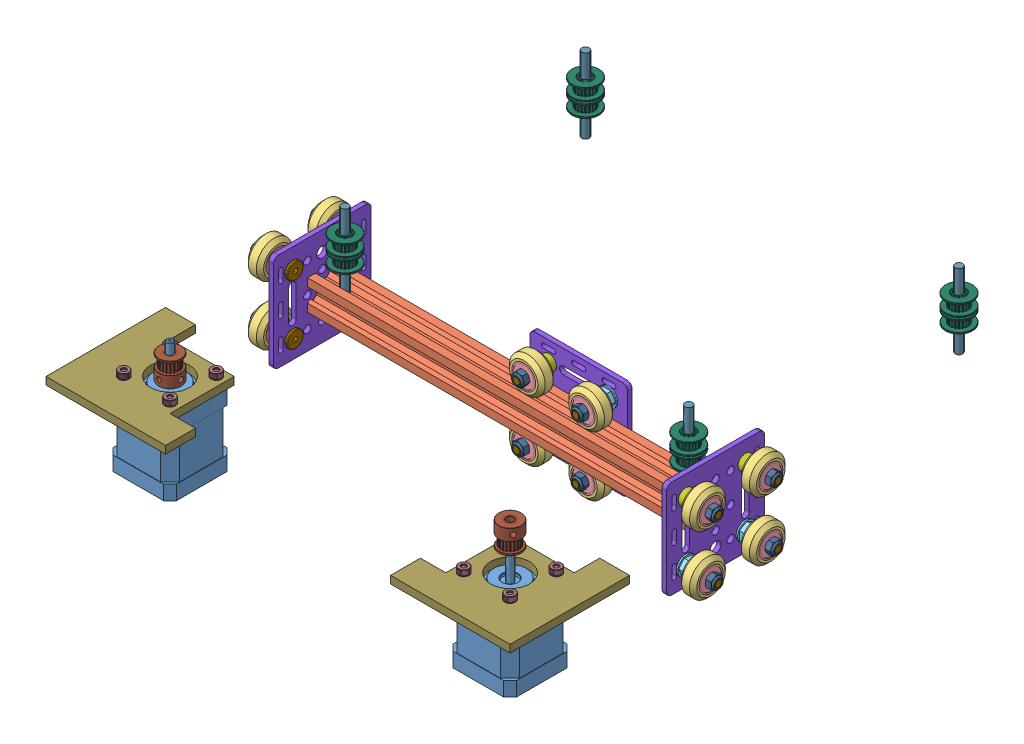
SolidWorks assembly XY_Axis_motion, configuration Default. Lengths in mm.
Overall size (310.6 92.07 339.8).
129 component instances, 15 part files, 36 mates.
Components (placement in the parent):
- DC_Steppers-1: DC_Steppers [6627T91] at (113.8 319.013 128.8) x (1 0 0) z (0 1 0) size (42.4 43.16 74.07)
- V-slot-aluminum-1: V-slot-aluminum [Gantry] at (130 320 10.5363) x (0 0 1) z (-1 0 0) size (20 20 260)
- DC_Steppers-2: DC_Steppers [6627T91] at (-113.8 319.013 128.8) x (1 0 0) z (0 1 0) size (42.4 43.16 74.07)
- 20mm Gantry Set.stp-1: 20mm Gantry Set.stp [Default] at (-145 320 10.5363) x (0 1 0) z (-1 0 0) size (71.69 71.99 27)
  - V-Wheel Solid Wheel.stp-1: V-Wheel Solid Wheel.stp [Default] at (31.4376 30.3864 0.786) x (0.859314 0.511448 0) z (0.511448 -0.859314 0) size (23.9 20 23.9)
    - Solid V-Wheel.stp-1: Solid V-Wheel.stp [Default] at (-15.2695 -5.901 2.9988) size (23.9 10.23 23.9)
    - Ball Bearing 625 2RS 5x16x5.stp-1: Ball Bearing 625 2RS 5x16x5.stp [Default] at (-15.2695 -5.671 2.9988) x (1 0 0) z (0 1 0) size (16 16 5)
    - Ball Bearing 625 2RS 5x16x5.stp-2: Ball Bearing 625 2RS 5x16x5.stp [Default] at (-15.2695 -0.671 2.9988) x (0.579467 0 0.814996) z (0 1 0) size (16 16 5)
    - Eccentric Spacer.stp-1: Eccentric Spacer.stp [Default] at (-15.2695 -6.671 2.9988) x (1 0 0) z (0 -1 0) size (12.5 12.5 9)
    - 1mm 5mm shim.stp-1: 1mm 5mm shim.stp [Default] at (-15.2695 -5.671 2.9988) x (1 0 0) z (0 -1 0) size (10 10 1)
  - V-Wheel Solid Wheel.stp-2: V-Wheel Solid Wheel.stp [Default] at (28.1904 -33.1373 0.786) x (0.363236 -0.931697 0) z (-0.931697 -0.363236 0) size (23.9 20 23.9)
    - Solid V-Wheel.stp-1: Solid V-Wheel.stp [Default] at (-15.2695 -5.901 2.9988) size (23.9 10.23 23.9)
    - Ball Bearing 625 2RS 5x16x5.stp-1: Ball Bearing 625 2RS 5x16x5.stp [Default] at (-15.2695 -5.671 2.9988) x (1 0 0) z (0 1 0) size (16 16 5)
    - Ball Bearing 625 2RS 5x16x5.stp-2: Ball Bearing 625 2RS 5x16x5.stp [Default] at (-15.2695 -0.671 2.9988) x (0.579467 0 0.814996) z (0 1 0) size (16 16 5)
    - Eccentric Spacer.stp-1: Eccentric Spacer.stp [Default] at (-15.2695 -6.671 2.9988) x (1 0 0) z (0 -1 0) size (12.5 12.5 9)
    - 1mm 5mm shim.stp-1: 1mm 5mm shim.stp [Default] at (-15.2695 -5.671 2.9988) x (1 0 0) z (0 -1 0) size (10 10 1)
  - V-Wheel Solid Wheel - spacer.stp-1: V-Wheel Solid Wheel - spacer.stp [Default] at (-4.4084 21.9251 0.786) x (0.997558 -0.069836 0) z (-0.069836 -0.997558 0) size (23.9 17 23.9)
    - Solid V-Wheel.stp-1: Solid V-Wheel.stp [Default] at (-15.2695 -5.901 2.9988) size (23.9 10.23 23.9)
    - Ball Bearing 625 2RS 5x16x5.stp-1: Ball Bearing 625 2RS 5x16x5.stp [Default] at (-15.2695 -5.671 2.9988) x (1 0 0) z (0 1 0) size (16 16 5)
    - Ball Bearing 625 2RS 5x16x5.stp-2: Ball Bearing 625 2RS 5x16x5.stp [Default] at (-15.2695 -0.671 2.9988) x (0.579467 0 0.814996) z (0 1 0) size (16 16 5)
    - 1mm 5mm shim.stp-1: 1mm 5mm shim.stp [Default] at (-15.2695 -5.671 2.9988) x (1 0 0) z (0 -1 0) size (10 10 1)
    - 6mm Spacer.stp-1: 6mm Spacer.stp [Default] at (-15.2695 -6.671 2.9988) x (1 0 0) z (0 -1 0) size (10 10 6)
  - V-Wheel Solid Wheel - spacer.stp-2: V-Wheel Solid Wheel - spacer.stp [Default] at (-6.8841 -11.3956 0.786) x (0.92416 0.382005 0) z (0.382005 -0.92416 0) size (23.9 17 23.9)
    - Solid V-Wheel.stp-1: Solid V-Wheel.stp [Default] at (-15.2695 -5.901 2.9988) size (23.9 10.23 23.9)
    - Ball Bearing 625 2RS 5x16x5.stp-1: Ball Bearing 625 2RS 5x16x5.stp [Default] at (-15.2695 -5.671 2.9988) x (1 0 0) z (0 1 0) size (16 16 5)
    - Ball Bearing 625 2RS 5x16x5.stp-2: Ball Bearing 625 2RS 5x16x5.stp [Default] at (-15.2695 -0.671 2.9988) x (0.579467 0 0.814996) z (0 1 0) size (16 16 5)
    - 1mm 5mm shim.stp-1: 1mm 5mm shim.stp [Default] at (-15.2695 -5.671 2.9988) x (1 0 0) z (0 -1 0) size (10 10 1)
    - 6mm Spacer.stp-1: 6mm Spacer.stp [Default] at (-15.2695 -6.671 2.9988) x (1 0 0) z (0 -1 0) size (10 10 6)
  - 20mm gantry plate.stp-1: 20mm gantry plate.stp [Default] at (0 0 -14.885) size (65.5 65.5 3)
  - M5x25 low profile screw.stp-1: M5x25 low profile screw.stp [Default] at (19.85 -20 -16.885) x (0.999998 -0.001827 0) z (0 0 1) size (11 11 27)
  - M5x25 low profile screw.stp-2: M5x25 low profile screw.stp [Default] at (19.85 20 -16.885) x (1 0.000182 0) z (0 0 1) size (11 11 27)
  - M5x25 low profile screw.stp-3: M5x25 low profile screw.stp [Default] at (-19.85 -20 -16.885) x (0.999594 -0.02849 0) z (0 0 1) size (11 11 27)
  - M5 Nylock.stp-1: M5 Nylock.stp [Default] at (19.85 -20 5.115) x (-0.864363 0.502868 0) z (0 0 1) size (9.24 9.25 5)
  - M5 Nylock.stp-2: M5 Nylock.stp [Default] at (19.85 20 5.115) x (0.463993 -0.885839 0) z (0 0 1) size (9.24 9.25 5)
  - M5 Nylock.stp-3: M5 Nylock.stp [Default] at (-19.85 20 5.115) x (-0.135333 -0.9908 0) z (0 0 1) size (9.24 9.25 5)
  - M5 Nylock.stp-4: M5 Nylock.stp [Default] at (-19.85 -20 5.115) x (-0.99254 -0.121918 0) z (0 0 1) size (9.24 9.25 5)
  - M5x25 low profile screw.stp-4: M5x25 low profile screw.stp [Default] at (-19.85 20 -16.885) x (1 0.000026 0) z (0 0 1) size (11 11 27)
- 20mm Gantry Set.stp-2: 20mm Gantry Set.stp [Default] at (29.6409 320 10.5363) size (71.69 71.99 27)
  - V-Wheel Solid Wheel.stp-1: V-Wheel Solid Wheel.stp [Default] at (31.4376 30.3864 0.786) x (0.859314 0.511448 0) z (0.511448 -0.859314 0) size (23.9 20 23.9)
    - Solid V-Wheel.stp-1: Solid V-Wheel.stp [Default] at (-15.2695 -5.901 2.9988) size (23.9 10.23 23.9)
    - Ball Bearing 625 2RS 5x16x5.stp-1: Ball Bearing 625 2RS 5x16x5.stp [Default] at (-15.2695 -5.671 2.9988) x (1 0 0) z (0 1 0) size (16 16 5)
    - Ball Bearing 625 2RS 5x16x5.stp-2: Ball Bearing 625 2RS 5x16x5.stp [Default] at (-15.2695 -0.671 2.9988) x (0.579467 0 0.814996) z (0 1 0) size (16 16 5)
    - Eccentric Spacer.stp-1: Eccentric Spacer.stp [Default] at (-15.2695 -6.671 2.9988) x (1 0 0) z (0 -1 0) size (12.5 12.5 9)
    - 1mm 5mm shim.stp-1: 1mm 5mm shim.stp [Default] at (-15.2695 -5.671 2.9988) x (1 0 0) z (0 -1 0) size (10 10 1)
  - V-Wheel Solid Wheel.stp-2: V-Wheel Solid Wheel.stp [Default] at (28.1904 -33.1373 0.786) x (0.363236 -0.931697 0) z (-0.931697 -0.363236 0) size (23.9 20 23.9)
    - Solid V-Wheel.stp-1: Solid V-Wheel.stp [Default] at (-15.2695 -5.901 2.9988) size (23.9 10.23 23.9)
    - Ball Bearing 625 2RS 5x16x5.stp-1: Ball Bearing 625 2RS 5x16x5.stp [Default] at (-15.2695 -5.671 2.9988) x (1 0 0) z (0 1 0) size (16 16 5)
    - Ball Bearing 625 2RS 5x16x5.stp-2: Ball Bearing 625 2RS 5x16x5.stp [Default] at (-15.2695 -0.671 2.9988) x (0.579467 0 0.814996) z (0 1 0) size (16 16 5)
    - Eccentric Spacer.stp-1: Eccentric Spacer.stp [Default] at (-15.2695 -6.671 2.9988) x (1 0 0) z (0 -1 0) size (12.5 12.5 9)
    - 1mm 5mm shim.stp-1: 1mm 5mm shim.stp [Default] at (-15.2695 -5.671 2.9988) x (1 0 0) z (0 -1 0) size (10 10 1)
  - V-Wheel Solid Wheel - spacer.stp-1: V-Wheel Solid Wheel - spacer.stp [Default] at (-4.4084 21.9251 0.786) x (0.997558 -0.069836 0) z (-0.069836 -0.997558 0) size (23.9 17 23.9)
    - Solid V-Wheel.stp-1: Solid V-Wheel.stp [Default] at (-15.2695 -5.901 2.9988) size (23.9 10.23 23.9)
    - Ball Bearing 625 2RS 5x16x5.stp-1: Ball Bearing 625 2RS 5x16x5.stp [Default] at (-15.2695 -5.671 2.9988) x (1 0 0) z (0 1 0) size (16 16 5)
    - Ball Bearing 625 2RS 5x16x5.stp-2: Ball Bearing 625 2RS 5x16x5.stp [Default] at (-15.2695 -0.671 2.9988) x (0.579467 0 0.814996) z (0 1 0) size (16 16 5)
    - 1mm 5mm shim.stp-1: 1mm 5mm shim.stp [Default] at (-15.2695 -5.671 2.9988) x (1 0 0) z (0 -1 0) size (10 10 1)
    - 6mm Spacer.stp-1: 6mm Spacer.stp [Default] at (-15.2695 -6.671 2.9988) x (1 0 0) z (0 -1 0) size (10 10 6)
  - V-Wheel Solid Wheel - spacer.stp-2: V-Wheel Solid Wheel - spacer.stp [Default] at (-6.8841 -11.3956 0.786) x (0.92416 0.382005 0) z (0.382005 -0.92416 0) size (23.9 17 23.9)
    - Solid V-Wheel.stp-1: Solid V-Wheel.stp [Default] at (-15.2695 -5.901 2.9988) size (23.9 10.23 23.9)
    - Ball Bearing 625 2RS 5x16x5.stp-1: Ball Bearing 625 2RS 5x16x5.stp [Default] at (-15.2695 -5.671 2.9988) x (1 0 0) z (0 1 0) size (16 16 5)
    - Ball Bearing 625 2RS 5x16x5.stp-2: Ball Bearing 625 2RS 5x16x5.stp [Default] at (-15.2695 -0.671 2.9988) x (0.579467 0 0.814996) z (0 1 0) size (16 16 5)
    - 1mm 5mm shim.stp-1: 1mm 5mm shim.stp [Default] at (-15.2695 -5.671 2.9988) x (1 0 0) z (0 -1 0) size (10 10 1)
    - 6mm Spacer.stp-1: 6mm Spacer.stp [Default] at (-15.2695 -6.671 2.9988) x (1 0 0) z (0 -1 0) size (10 10 6)
  - 20mm gantry plate.stp-1: 20mm gantry plate.stp [Default] at (0 0 -14.885) size (65.5 65.5 3)
  - M5x25 low profile screw.stp-1: M5x25 low profile screw.stp [Default] at (19.85 -20 -16.885) x (0.999998 -0.001827 0) z (0 0 1) size (11 11 27)
  - M5x25 low profile screw.stp-2: M5x25 low profile screw.stp [Default] at (19.85 20 -16.885) x (1 0.000182 0) z (0 0 1) size (11 11 27)
  - M5x25 low profile screw.stp-3: M5x25 low profile screw.stp [Default] at (-19.85 -20 -16.885) x (0.999594 -0.02849 0) z (0 0 1) size (11 11 27)
  - M5 Nylock.stp-1: M5 Nylock.stp [Default] at (19.85 -20 5.115) x (-0.864363 0.502868 0) z (0 0 1) size (9.24 9.25 5)
  - M5 Nylock.stp-2: M5 Nylock.stp [Default] at (19.85 20 5.115) x (0.463993 -0.885839 0) z (0 0 1) size (9.24 9.25 5)
  - M5 Nylock.stp-3: M5 Nylock.stp [Default] at (-19.85 20 5.115) x (-0.135333 -0.9908 0) z (0 0 1) size (9.24 9.25 5)
  - M5 Nylock.stp-4: M5 Nylock.stp [Default] at (-19.85 -20 5.115) x (-0.99254 -0.121918 0) z (0 0 1) size (9.24 9.25 5)
  - M5x25 low profile screw.stp-4: M5x25 low profile screw.stp [Default] at (-19.85 20 -16.885) x (1 0.000026 0) z (0 0 1) size (11 11 27)
- TimingPulley-1: TimingPulley [Výchozí] at (113.8 366.032 128.8) x (0.837169 0 0.546944) z (0.546944 0 -0.837169) size (15 16 15)
- TimingPulley-2: TimingPulley [Výchozí] at (-113.8 333.032 128.8) size (15 16 15)
- 20mm Gantry Set.stp-3: 20mm Gantry Set.stp [Default] at (145 320 10.5363) x (0 -1 0) z (1 0 0) size (71.69 71.99 27)
  - V-Wheel Solid Wheel.stp-1: V-Wheel Solid Wheel.stp [Default] at (31.4376 30.3864 0.786) x (0.859314 0.511448 0) z (0.511448 -0.859314 0) size (23.9 20 23.9)
    - Solid V-Wheel.stp-1: Solid V-Wheel.stp [Default] at (-15.2695 -5.901 2.9988) size (23.9 10.23 23.9)
    - Ball Bearing 625 2RS 5x16x5.stp-1: Ball Bearing 625 2RS 5x16x5.stp [Default] at (-15.2695 -5.671 2.9988) x (1 0 0) z (0 1 0) size (16 16 5)
    - Ball Bearing 625 2RS 5x16x5.stp-2: Ball Bearing 625 2RS 5x16x5.stp [Default] at (-15.2695 -0.671 2.9988) x (0.579467 0 0.814996) z (0 1 0) size (16 16 5)
    - Eccentric Spacer.stp-1: Eccentric Spacer.stp [Default] at (-15.2695 -6.671 2.9988) x (1 0 0) z (0 -1 0) size (12.5 12.5 9)
    - 1mm 5mm shim.stp-1: 1mm 5mm shim.stp [Default] at (-15.2695 -5.671 2.9988) x (1 0 0) z (0 -1 0) size (10 10 1)
  - V-Wheel Solid Wheel.stp-2: V-Wheel Solid Wheel.stp [Default] at (28.1904 -33.1373 0.786) x (0.363236 -0.931697 0) z (-0.931697 -0.363236 0) size (23.9 20 23.9)
    - Solid V-Wheel.stp-1: Solid V-Wheel.stp [Default] at (-15.2695 -5.901 2.9988) size (23.9 10.23 23.9)
    - Ball Bearing 625 2RS 5x16x5.stp-1: Ball Bearing 625 2RS 5x16x5.stp [Default] at (-15.2695 -5.671 2.9988) x (1 0 0) z (0 1 0) size (16 16 5)
    - Ball Bearing 625 2RS 5x16x5.stp-2: Ball Bearing 625 2RS 5x16x5.stp [Default] at (-15.2695 -0.671 2.9988) x (0.579467 0 0.814996) z (0 1 0) size (16 16 5)
    - Eccentric Spacer.stp-1: Eccentric Spacer.stp [Default] at (-15.2695 -6.671 2.9988) x (1 0 0) z (0 -1 0) size (12.5 12.5 9)
    - 1mm 5mm shim.stp-1: 1mm 5mm shim.stp [Default] at (-15.2695 -5.671 2.9988) x (1 0 0) z (0 -1 0) size (10 10 1)
  - V-Wheel Solid Wheel - spacer.stp-1: V-Wheel Solid Wheel - spacer.stp [Default] at (-4.4084 21.9251 0.786) x (0.997558 -0.069836 0) z (-0.069836 -0.997558 0) size (23.9 17 23.9)
    - Solid V-Wheel.stp-1: Solid V-Wheel.stp [Default] at (-15.2695 -5.901 2.9988) size (23.9 10.23 23.9)
    - Ball Bearing 625 2RS 5x16x5.stp-1: Ball Bearing 625 2RS 5x16x5.stp [Default] at (-15.2695 -5.671 2.9988) x (1 0 0) z (0 1 0) size (16 16 5)
    - Ball Bearing 625 2RS 5x16x5.stp-2: Ball Bearing 625 2RS 5x16x5.stp [Default] at (-15.2695 -0.671 2.9988) x (0.579467 0 0.814996) z (0 1 0) size (16 16 5)
    - 1mm 5mm shim.stp-1: 1mm 5mm shim.stp [Default] at (-15.2695 -5.671 2.9988) x (1 0 0) z (0 -1 0) size (10 10 1)
    - 6mm Spacer.stp-1: 6mm Spacer.stp [Default] at (-15.2695 -6.671 2.9988) x (1 0 0) z (0 -1 0) size (10 10 6)
  - V-Wheel Solid Wheel - spacer.stp-2: V-Wheel Solid Wheel - spacer.stp [Default] at (-6.8841 -11.3956 0.786) x (0.92416 0.382005 0) z (0.382005 -0.92416 0) size (23.9 17 23.9)
    - Solid V-Wheel.stp-1: Solid V-Wheel.stp [Default] at (-15.2695 -5.901 2.9988) size (23.9 10.23 23.9)
    - Ball Bearing 625 2RS 5x16x5.stp-1: Ball Bearing 625 2RS 5x16x5.stp [Default] at (-15.2695 -5.671 2.9988) x (1 0 0) z (0 1 0) size (16 16 5)
    - Ball Bearing 625 2RS 5x16x5.stp-2: Ball Bearing 625 2RS 5x16x5.stp [Default] at (-15.2695 -0.671 2.9988) x (0.579467 0 0.814996) z (0 1 0) size (16 16 5)
    - 1mm 5mm shim.stp-1: 1mm 5mm shim.stp [Default] at (-15.2695 -5.671 2.9988) x (1 0 0) z (0 -1 0) size (10 10 1)
    - 6mm Spacer.stp-1: 6mm Spacer.stp [Default] at (-15.2695 -6.671 2.9988) x (1 0 0) z (0 -1 0) size (10 10 6)
  - 20mm gantry plate.stp-1: 20mm gantry plate.stp [Default] at (0 0 -14.885) size (65.5 65.5 3)
  - M5x25 low profile screw.stp-1: M5x25 low profile screw.stp [Default] at (19.85 -20 -16.885) x (0.999998 -0.001827 0) z (0 0 1) size (11 11 27)
  - M5x25 low profile screw.stp-2: M5x25 low profile screw.stp [Default] at (19.85 20 -16.885) x (1 0.000182 0) z (0 0 1) size (11 11 27)
  - M5x25 low profile screw.stp-3: M5x25 low profile screw.stp [Default] at (-19.85 -20 -16.885) x (0.999594 -0.02849 0) z (0 0 1) size (11 11 27)
  - M5 Nylock.stp-1: M5 Nylock.stp [Default] at (19.85 -20 5.115) x (-0.864363 0.502868 0) z (0 0 1) size (9.24 9.25 5)
  - M5 Nylock.stp-2: M5 Nylock.stp [Default] at (19.85 20 5.115) x (0.463993 -0.885839 0) z (0 0 1) size (9.24 9.25 5)
  - M5 Nylock.stp-3: M5 Nylock.stp [Default] at (-19.85 20 5.115) x (-0.135333 -0.9908 0) z (0 0 1) size (9.24 9.25 5)
  - M5 Nylock.stp-4: M5 Nylock.stp [Default] at (-19.85 -20 5.115) x (-0.99254 -0.121918 0) z (0 0 1) size (9.24 9.25 5)
  - M5x25 low profile screw.stp-4: M5x25 low profile screw.stp [Default] at (-19.85 20 -16.885) x (1 0.000026 0) z (0 0 1) size (11 11 27)
- MotorMount-1: MotorMount [Default] at (155.3 330 90.3) x (-1 0 0) z (0 0 -1) size (80 5 80)
- MotorMount-2: MotorMount [Default] at (-155.3 335 90.3) x (1 0 0) z (0 0 -1) size (80 5 80)
- 91290A144_Black-Oxide Alloy Steel Socket Head Screw-1: 91290A144_Black-Oxide Alloy Steel Socket Head Screw [91290A144] at (129.3 332 113.3) x (0.837169 0 0.546944) z (0 1 0) size (7 7 14.17)
- 91290A144_Black-Oxide Alloy Steel Socket Head Screw-2: 91290A144_Black-Oxide Alloy Steel Socket Head Screw [91290A144] at (129.3 332 144.3) x (-0.546944 0 0.837169) z (0 1 0) size (7 7 14.17)
- 91290A144_Black-Oxide Alloy Steel Socket Head Screw-3: 91290A144_Black-Oxide Alloy Steel Socket Head Screw [91290A144] at (98.3 332 144.3) x (-0.837169 0 -0.546944) z (0 1 0) size (7 7 14.17)
- 91290A144_Black-Oxide Alloy Steel Socket Head Screw-4: 91290A144_Black-Oxide Alloy Steel Socket Head Screw [91290A144] at (98.3 332 113.3) x (0.546944 0 -0.837169) z (0 1 0) size (7 7 14.17)
- 91290A144_Black-Oxide Alloy Steel Socket Head Screw-5: 91290A144_Black-Oxide Alloy Steel Socket Head Screw [91290A144] at (-129.3 332 113.3) x (0.837169 0 -0.546944) z (0 1 0) size (7 7 14.17)
- 91290A144_Black-Oxide Alloy Steel Socket Head Screw-6: 91290A144_Black-Oxide Alloy Steel Socket Head Screw [91290A144] at (-129.3 332 144.3) x (-0.546944 0 -0.837169) z (0 1 0) size (7 7 14.17)
- 91290A144_Black-Oxide Alloy Steel Socket Head Screw-7: 91290A144_Black-Oxide Alloy Steel Socket Head Screw [91290A144] at (-98.3 332 144.3) x (-0.837169 0 0.546944) z (0 1 0) size (7 7 14.17)
- 91290A144_Black-Oxide Alloy Steel Socket Head Screw-8: 91290A144_Black-Oxide Alloy Steel Socket Head Screw [91290A144] at (-98.3 332 113.3) x (0.546944 0 0.837169) z (0 1 0) size (7 7 14.17)
- pulleyRod-1: pulleyRod [Default] at (115.115 324.025 10.5) size (5 50 5)
- pulleyRod-2: pulleyRod [Default] at (125 324.025 -160.5) size (5 50 5)
- pulleyRod-3: pulleyRod [Default] at (-125 324.025 -160.5) size (5 50 5)
- pulleyRod-4: pulleyRod [Default] at (-114.9555 324.025 10.5) size (5 50 5)
- IdlerPulley-1: IdlerPulley [3693N12] at (-114.9555 344.782 10.5) x (1 0 0) z (0 -1 0) size (18 18 8.5)
- IdlerPulley-2: IdlerPulley [3693N12] at (-125 344.782 -160.5) x (1 0 0) z (0 1 0) size (18 18 8.5)
- IdlerPulley-3: IdlerPulley [3693N12] at (-125 354.282 -160.5) x (1 0 0) z (0 1 0) size (18 18 8.5)
- IdlerPulley-4: IdlerPulley [3693N12] at (125 344.782 -160.5) x (1 0 0) z (0 1 0) size (18 18 8.5)
- IdlerPulley-5: IdlerPulley [3693N12] at (-114.9555 354.282 10.5) x (1 0 0) z (0 1 0) size (18 18 8.5)
- IdlerPulley-6: IdlerPulley [3693N12] at (115.115 344.782 10.5) x (1 0 0) z (0 1 0) size (18 18 8.5)
- IdlerPulley-7: IdlerPulley [3693N12] at (115.115 354.282 10.5) x (1 0 0) z (0 1 0) size (18 18 8.5)
- IdlerPulley-8: IdlerPulley [3693N12] at (125 354.282 -160.5) x (1 0 0) z (0 1 0) size (18 18 8.5)
Mates (geometry in assembly coordinates):
- Concentric29: concentric aligned: cylinder of 20mm Gantry Set.stp-1/20mm gantry plate.stp-1 through (-133.115 320 10.5363) axis (1 0 0) radius 2.5; cylinder of V-slot-aluminum-1 through (-130 320 10.5363) axis (1 0 0) radius 2.1
- Coincident76: coincident aligned: plane of 20mm Gantry Set.stp-1 through (-145 320 10.5363) normal (0 1 0); plane of V-slot-aluminum-1 through (130 320 10.5363) normal (0 1 0)
- Coincident77: coincident aligned: plane of V-slot-aluminum-1 through (130 320 10.5363) normal (0 1 0); plane of 20mm Gantry Set.stp-2 through (29.6409 320 10.5363) normal (0 1 0)
- Coincident78: coincident aligned: plane of V-slot-aluminum-1 through (130 320 10.5363) normal (0 0 1); plane of 20mm Gantry Set.stp-2 through (29.6409 320 10.5363) normal (0 0 1)
- Concentric28: concentric anti-aligned: cylinder of DC_Steppers-1 through (113.8 356.032 128.8) axis (0 -1 0) radius 2.25; cylinder of TimingPulley-1 through (113.8 351.232 128.8) axis (0 1 0) radius 2.5
- Distance1: distance = 6 mm anti-aligned: plane of DC_Steppers-1 through (113.8 356.032 128.8) normal (0 1 0); plane of TimingPulley-1 through (113.8 350.032 128.8) normal (0 -1 0)
- Concentric30: concentric aligned: cylinder of DC_Steppers-2 through (-113.8 356.032 128.8) axis (0 -1 0) radius 2.25; cylinder of TimingPulley-2 through (-113.8 347.832 128.8) axis (0 -1 0) radius 2.5
- Distance2: distance = 7 mm aligned: plane of DC_Steppers-2 through (-113.8 356.032 128.8) normal (0 1 0); plane of TimingPulley-2 through (-113.8 349.032 128.8) normal (0 1 0)
- Concentric31: concentric anti-aligned: cylinder of 20mm Gantry Set.stp-3/20mm gantry plate.stp-1 through (133.115 320 10.5363) axis (-1 0 0) radius 2.5; cylinder of 20mm Gantry Set.stp-1/20mm gantry plate.stp-1 through (-133.115 320 10.5363) axis (1 0 0) radius 2.5
- Coincident80: coincident anti-aligned: plane of DC_Steppers-1 through (113.8 330 128.8) normal (0 1 0); plane of MotorMount-1 through (155.3 330 90.3) normal (0 -1 0)
- Concentric32: concentric aligned: circle of DC_Steppers-1; cylinder of MotorMount-1 through (98.3 335 113.3) axis (0 -1 0) radius 1.6
- Concentric33: concentric aligned: cylinder of DC_Steppers-1 through (113.8 356.032 128.8) axis (0 -1 0) radius 2.25; cylinder of MotorMount-1 through (113.8 335 128.8) axis (0 -1 0) radius 13
- Concentric34: concentric aligned: cylinder of MotorMount-1 through (129.3 335 113.3) axis (0 -1 0) radius 1.6; circle of 91290A144_Black-Oxide Alloy Steel Socket Head Screw-1
- Coincident81: coincident anti-aligned: plane of MotorMount-1 through (155.3 335 90.3) normal (0 1 0); plane of 91290A144_Black-Oxide Alloy Steel Socket Head Screw-1 through (126.5373 335 111.4951) normal (0 -1 0)
- Coincident84: coincident anti-aligned: plane of V-slot-aluminum-1 through (-130 324.025 7.6963) normal (0 1 0); plane of pulleyRod-1 through (115.115 324.025 10.5) normal (0 -1 0)
- Distance20: distance = 10.5 mm: cylinder of pulleyRod-1 through (115.115 374.025 10.5) axis (0 -1 0) radius 2.5
- Distance21: distance = 15 mm: cylinder of pulleyRod-1 through (115.115 374.025 10.5) axis (0 -1 0) radius 2.5; plane of 20mm Gantry Set.stp-3/20mm gantry plate.stp-1 through (130.115 320 10.5363) normal (-1 0 0)
- Concentric35: concentric anti-aligned: cylinder of pulleyRod-1 through (115.115 374.025 10.5) axis (0 -1 0) radius 2.5; cylinder of IdlerPulley-6 through (115.115 349.032 10.5) axis (0 1 0) radius 2.5
- Concentric36: concentric anti-aligned: cylinder of pulleyRod-1 through (115.115 374.025 10.5) axis (0 -1 0) radius 2.5; cylinder of IdlerPulley-7 through (115.115 358.532 10.5) axis (0 1 0) radius 2.5
- Concentric37: concentric anti-aligned: cylinder of pulleyRod-2 through (125 374.025 -160.5) axis (0 -1 0) radius 2.5; cylinder of IdlerPulley-4 through (125 349.032 -160.5) axis (0 1 0) radius 2.5
- Concentric38: concentric anti-aligned: cylinder of pulleyRod-2 through (125 374.025 -160.5) axis (0 -1 0) radius 2.5; cylinder of IdlerPulley-8 through (125 358.532 -160.5) axis (0 1 0) radius 2.5
- Concentric39: concentric anti-aligned: cylinder of pulleyRod-3 through (-125 374.025 -160.5) axis (0 -1 0) radius 2.5; cylinder of IdlerPulley-2 through (-125 349.032 -160.5) axis (0 1 0) radius 2.5
- Concentric40: concentric anti-aligned: cylinder of pulleyRod-3 through (-125 374.025 -160.5) axis (0 -1 0) radius 2.5; cylinder of IdlerPulley-3 through (-125 358.532 -160.5) axis (0 1 0) radius 2.5
- Distance27: distance = 10.5 mm: cylinder of pulleyRod-4 through (-114.9555 374.025 10.5) axis (0 -1 0) radius 2.5
- Distance28: distance = 15.1595 mm: cylinder of pulleyRod-4 through (-114.9555 374.025 10.5) axis (0 -1 0) radius 2.5; plane of 20mm Gantry Set.stp-1/20mm gantry plate.stp-1 through (-130.115 320 10.5363) normal (1 0 0)
- Coincident89: coincident anti-aligned: plane of V-slot-aluminum-1 through (-130 324.025 7.6963) normal (0 1 0); plane of pulleyRod-4 through (-114.9555 324.025 10.5) normal (0 -1 0)
- Concentric41: concentric anti-aligned: cylinder of pulleyRod-4 through (-114.9555 374.025 10.5) axis (0 -1 0) radius 2.5; circle of IdlerPulley-1
- Concentric42: concentric anti-aligned: cylinder of pulleyRod-4 through (-114.9555 374.025 10.5) axis (0 -1 0) radius 2.5; cylinder of IdlerPulley-5 through (-114.9555 358.532 10.5) axis (0 1 0) radius 2.5
- Coincident90: coincident aligned: plane of TimingPulley-2 through (-113.8 349.032 128.8) normal (0 1 0); plane of IdlerPulley-1 through (-114.9555 349.032 19.5) normal (0 1 0)
- Coincident92: coincident aligned: plane of TimingPulley-2 through (-113.8 349.032 128.8) normal (0 1 0); plane of IdlerPulley-2 through (-125 349.032 -169.5) normal (0 1 0)
- Coincident93: coincident aligned: plane of TimingPulley-1 through (113.8 350.032 128.8) normal (0 -1 0); circle of IdlerPulley-3
- Coincident94: coincident aligned: plane of TimingPulley-2 through (-113.8 349.032 128.8) normal (0 1 0); plane of IdlerPulley-4 through (125 349.032 -169.5) normal (0 1 0)
- Coincident91: coincident aligned: circle of TimingPulley-1; plane of IdlerPulley-5 through (-114.9555 350.032 1.5) normal (0 -1 0)
- Coincident96: coincident aligned: plane of TimingPulley-2 through (-113.8 349.032 128.8) normal (0 1 0); plane of IdlerPulley-6 through (115.115 349.032 1.5) normal (0 1 0)
- Coincident97: coincident aligned: plane of TimingPulley-1 through (113.8 350.032 128.8) normal (0 -1 0); plane of IdlerPulley-7 through (115.115 350.032 1.5) normal (0 -1 0)
- Coincident95: coincident aligned: plane of TimingPulley-1 through (113.8 350.032 128.8) normal (0 -1 0); circle of IdlerPulley-8
